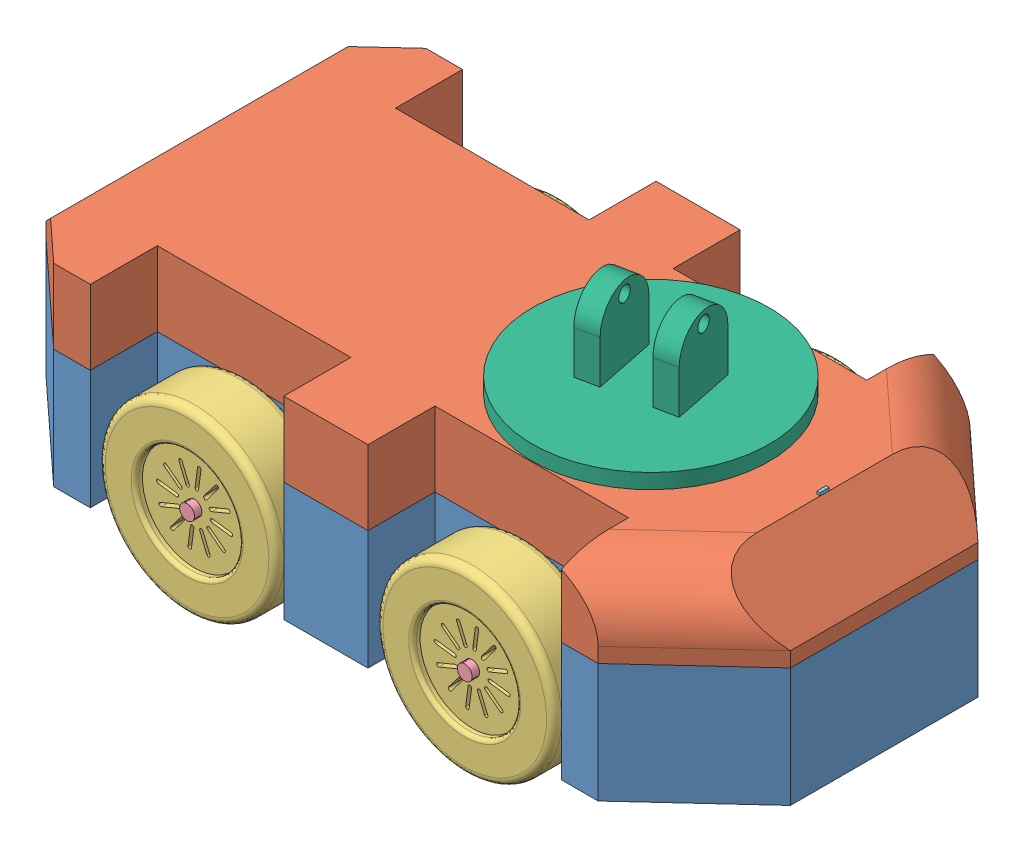
SolidWorks assembly cafe_robot_d, configuration Default. Lengths in mm.
Overall size (510 529.24 660.46).
12 component instances, 6 part files, 40 mates.
Components (placement in the parent):
- base-1: base [Default] at (0 110 0) x (-1 0 0) z (0 -1 0) size (500 250 80)
- cover-1: cover [Default] at (0 160 0) x (-1 0 0) z (0 -1 0) size (500 250 50)
- wheel2-1: wheel2 [Default] at (-343.2557 60 -210) x (0 0 -1) z (-0.825904 0.56381 0) size (40 120 120)
- wheel2-2: wheel2 [Default] at (-156.7443 60 -40) x (0 0 1) z (-0.383049 0.923728 0) size (40 120 120)
- wheel2-3: wheel2 [Default] at (-156.7443 60 -210) x (0 0 -1) z (-0.825904 0.56381 0) size (40 120 120)
- wheel2-4: wheel2 [Default] at (-343.2557 60 -40) x (0 0 1) z (-0.383049 0.923728 0) size (40 120 120)
- shaftt-1: shaftt [Default] at (-156.0595 58.3486 0) x (0.923728 0.383049 0) z (-0.383049 0.923728 0) size (10 250 10)
- shaftt-2: shaftt [Default] at (-342.5709 58.3486 0) x (0.923728 0.383049 0) z (-0.383049 0.923728 0) size (10 250 10)
- lasersen-1: lasersen [Default] at (-40 160 -124) x (-1 0 0) z (0 0 1) size (2 2 2)
- lasersen-2: lasersen [Default] at (-42 162 -128) x (1 0 0) z (0 1 0) size (2 2 2)
- lasersen-3: lasersen [Default] at (-40 160 -122) x (-1 0 0) z (0 0 1) size (2 2 2)
- armbase1-1: armbase1 [Default] at (-156.7443 160 -125) x (0.979698 0 -0.200481) z (0.200481 0 0.979698) size (159 62 159)
Mates (geometry in assembly coordinates):
- Coincident1: coincident anti-aligned: plane of base-1 through (0 110 0) normal (0 1 0); plane of cover-1 through (0 110 0) normal (0 -1 0)
- Coincident2: coincident aligned: plane of base-1 through (0 30 -188.0038) normal (0.678366 0 -0.734724); plane of cover-1 through (0 110 -188.0038) normal (0.678366 0 -0.734724)
- Coincident3: coincident aligned: plane of base-1 through (0 30 -61.9962) normal (0.678366 0 0.734724); plane of cover-1 through (0 110 -61.9962) normal (0.678366 0 0.734724)
- Coincident4: coincident aligned: plane of base-1 through (0 30 -188.0038) normal (1 0 0); plane of cover-1 through (0 110 -188.0038) normal (1 0 0)
- Coincident5: coincident aligned: plane of base-1 through (-91.7443 30 -250) normal (-1 0 0); plane of cover-1 through (-91.7443 110 -250) normal (-1 0 0)
- Coincident6: coincident aligned: plane of base-1 through (-91.7443 30 -205) normal (0 0 -1); plane of cover-1 through (-91.7443 110 -205) normal (0 0 -1)
- Concentric6: concentric anti-aligned: cylinder of base-1 through (-156.7443 60 30.232) axis (0 0 -1) radius 5; cylinder of shaftt-1 through (-156.7443 60 -250) axis (0 0 1) radius 5
- Coincident14: coincident aligned: plane of base-1 through (-221.7443 30 -250) normal (0 0 -1); plane of shaftt-1 through (-156.7443 60 -250) normal (0 0 -1)
- Concentric7: concentric anti-aligned: cylinder of base-1 through (-343.2557 60 30.232) axis (0 0 -1) radius 5; cylinder of shaftt-2 through (-343.2557 60 -250) axis (0 0 1) radius 5
- Coincident15: coincident aligned: plane of base-1 through (-221.7443 30 -250) normal (0 0 -1); plane of shaftt-2 through (-343.2557 60 -250) normal (0 0 -1)
- Concentric8: concentric aligned: cylinder of wheel2-1 through (-343.2557 60 -210) axis (0 0 1) radius 5; cylinder of shaftt-2 through (-343.2557 60 -250) axis (0 0 1) radius 5
- Coincident16: coincident aligned: plane of wheel2-1 through (-377.0843 10.4457 -250) normal (0 0 -1); plane of shaftt-2 through (-343.2557 60 -250) normal (0 0 -1)
- Concentric9: concentric anti-aligned: cylinder of wheel2-4 through (-343.2557 60 -40) axis (0 0 -1) radius 5; cylinder of shaftt-2 through (-343.2557 60 -250) axis (0 0 1) radius 5
- Coincident17: coincident aligned: plane of wheel2-4 through (-287.832 82.9829 0) normal (0 0 1); plane of shaftt-2 through (-343.2557 60 0) normal (0 0 1)
- Concentric10: concentric anti-aligned: cylinder of wheel2-2 through (-156.7443 60 -40) axis (0 0 -1) radius 5; cylinder of shaftt-1 through (-156.7443 60 -250) axis (0 0 1) radius 5
- Coincident18: coincident aligned: plane of wheel2-2 through (-101.3206 82.9829 0) normal (0 0 1); plane of shaftt-1 through (-156.7443 60 0) normal (0 0 1)
- Concentric11: concentric aligned: cylinder of wheel2-3 through (-156.7443 60 -210) axis (0 0 1) radius 5; cylinder of shaftt-1 through (-156.7443 60 -250) axis (0 0 1) radius 5
- Coincident19: coincident aligned: plane of wheel2-3 through (-190.5729 10.4457 -250) normal (0 0 -1); plane of shaftt-1 through (-156.7443 60 -250) normal (0 0 -1)
- Tangent1: tangent anti-aligned: cylinder of wheel2-3 through (-156.7443 60 -210) axis (0 0 1) radius 60
- Tangent2: tangent anti-aligned: cylinder of wheel2-1 through (-343.2557 60 -210) axis (0 0 1) radius 60
- Tangent3: tangent anti-aligned: cylinder of wheel2-2 through (-156.7443 60 -40) axis (0 0 -1) radius 60
- Tangent4: tangent anti-aligned: cylinder of wheel2-4 through (-343.2557 60 -40) axis (0 0 -1) radius 60
- Coincident21: coincident aligned: plane of cover-1 through (-221.7443 110 0) normal (0 0 1)
- Coincident22: coincident aligned: plane of base-1 through (0 30 -188.0038) normal (1 0 0)
- Coincident23: coincident anti-aligned: plane of cover-1 through (0 160 0) normal (0 1 0); plane of lasersen-1 through (-42 160 -124) normal (0 -1 0)
- Coincident24: coincident: line of cover-1 through (-40 160 -79.5067) axis (0 0 -1); plane of lasersen-1 through (-40 160 -124) normal (1 0 0)
- Coincident25: coincident: moEndPointRef_w of cover-1; unknown of lasersen-1
- Coincident26: coincident anti-aligned: plane of cover-1 through (0 160 0) normal (0 1 0); plane of lasersen-3 through (-42 160 -122) normal (0 -1 0)
- Coincident27: coincident: line of cover-1 through (-40 160 -79.5067) axis (0 0 -1); plane of lasersen-3 through (-40 160 -122) normal (1 0 0)
- Coincident28: coincident anti-aligned: plane of lasersen-1 through (-42 160 -124) normal (0 0 1); plane of lasersen-3 through (-42 160 -124) normal (0 0 -1)
- Coincident29: coincident anti-aligned: plane of cover-1 through (0 160 0) normal (0 1 0); plane of lasersen-2 through (-40 160 -128) normal (0 -1 0)
- Coincident31: coincident aligned: line of cover-1 through (-40 160 -79.5067) axis (0 0 -1); line of lasersen-2 through (-40 160 -126) axis (0 0 -1)
- Coincident33: coincident anti-aligned: plane of lasersen-1 through (-42 160 -126) normal (0 0 -1); plane of lasersen-2 through (-40 162 -126) normal (0 0 1)
- Concentric12: concentric anti-aligned: cylinder of Part1arm1-1 through (-25.4981 212 -151.8577) axis (-0.979698 0 0.200481) radius 5; cylinder of armbase1-1 through (-236.5583 212 -108.6672) axis (0.979698 0 -0.200481) radius 5
- Coincident34: coincident anti-aligned: plane of Part1arm1-1 through (-180.5031 372.3404 -315.9227) normal (0.979698 0 -0.200481); plane of armbase1-1 through (-142.0488 220 -128.0072) normal (-0.979698 0 0.200481)
- Concentric13: concentric anti-aligned: cylinder of Part1arm1-1 through (-63.9524 372.3404 -339.7731) axis (-0.979698 0 0.200481) radius 5; cylinder of Part1arm2-1 through (-280.4322 372.3404 -295.4736) axis (0.979698 0 -0.200481) radius 5
- Coincident35: coincident anti-aligned: plane of Part1arm1-1 through (-180.5031 372.3404 -315.9227) normal (0.979698 0 -0.200481); plane of Part1arm2-1 through (-180.5031 372.3404 -315.9227) normal (-0.979698 0 0.200481)
- Coincident56: coincident anti-aligned: plane of arm4-1 through (-213.1609 492.1121 -625.1528) normal (-0.979698 0 0.200481); plane of Part1arm2-1 through (-151.1121 372.3404 -321.9371) normal (0.979698 0 -0.200481)
- Concentric15: concentric anti-aligned: cylinder of cover-1 through (-156.7443 158 -125) axis (0 1 0) radius 30.1; cylinder of armbase1-1 through (-156.7443 160 -125) axis (0 -1 0) radius 33.7261
- Coincident57: coincident anti-aligned: plane of cover-1 through (0 160 0) normal (0 1 0); plane of armbase1-1 through (-156.7443 160 -125) normal (0 -1 0)
